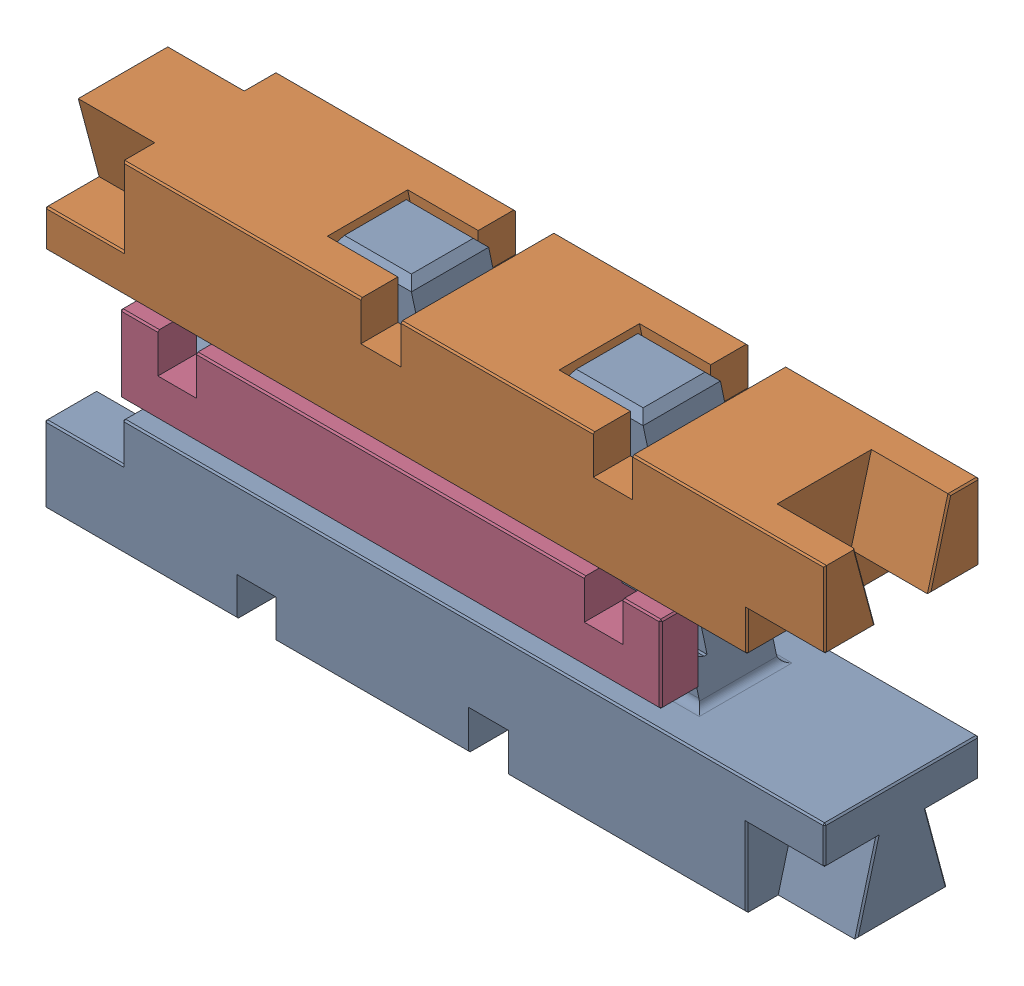
SolidWorks assembly Main Assembly, configuration Default. Lengths in mm.
Overall size (101.05 43.98 20).
4 component instances, 2 part files, 7 mates.
Components (placement in the parent):
- dish rack-1: dish rack [Default] at (635.291 834.6362 1296.0919) size (100.98 43.98 20)
- dish rack-3: dish rack [Default] at (656.3394 848.6109 1296.0919) x (-1 0 0) z (0 0 1) size (100.98 43.98 20)
- dish rod-2: dish rod [Default] at (631.9601 841.7679 1286.1919) size (70 10 6.78)
- dish rod-3: dish rod [Default] at (639.9717 841.7679 1305.9919) x (-1 0 0) z (0 0 -1) size (70 10 6.78)
Mates (geometry in assembly coordinates):
- Slant: distance = 0.4 mm anti-aligned: plane of dish rack-1 through (664.5034 819.688 1301.0919) normal (-0.965926 -0.258819 0); plane of dish rack-3 through (656.3394 848.6109 1291.0919) normal (0.965926 0.258819 0)
- Distance3: distance = 0.2 mm anti-aligned: plane of dish rack-1 through (635.291 834.6362 1290.8919) normal (0 0 1); plane of dish rack-3 through (686.3394 848.6109 1291.0919) normal (0 0 -1)
- LimitDistance1: limit distance = 13.9747 mm anti-aligned: plane of dish rack-1 through (635.291 834.6362 1296.0919) normal (0 1 0); plane of dish rack-3 through (656.3394 848.6109 1296.0919) normal (0 -1 0)
- Distance5: distance = 0.1 mm anti-aligned: plane of dish rod-2 through (662.4017 844.2679 1292.9713) normal (0 0 1); plane of dish rack-1 through (595.291 834.6362 1293.0713) normal (0 0 -1)
- Distance6: distance = 0.1 mm anti-aligned: plane of dish rack-1 through (595.291 844.112 1292.643) normal (0 -0.939693 0.34202); plane of dish rod-2 through (662.4017 843.4899 1291.2261) normal (0 0.939693 -0.34202)
- Distance7: distance = 0.1 mm anti-aligned: plane of dish rod-3 through (609.5302 844.2679 1299.2125) normal (0 0 -1); plane of dish rack-1 through (595.291 834.6362 1299.1125) normal (0 0 1)
- Distance8: distance = 0.1 mm anti-aligned: plane of dish rack-1 through (595.291 844.112 1299.5408) normal (0 -0.939693 -0.34202); plane of dish rod-3 through (609.5302 843.4899 1300.9577) normal (0 0.939693 0.34202)
